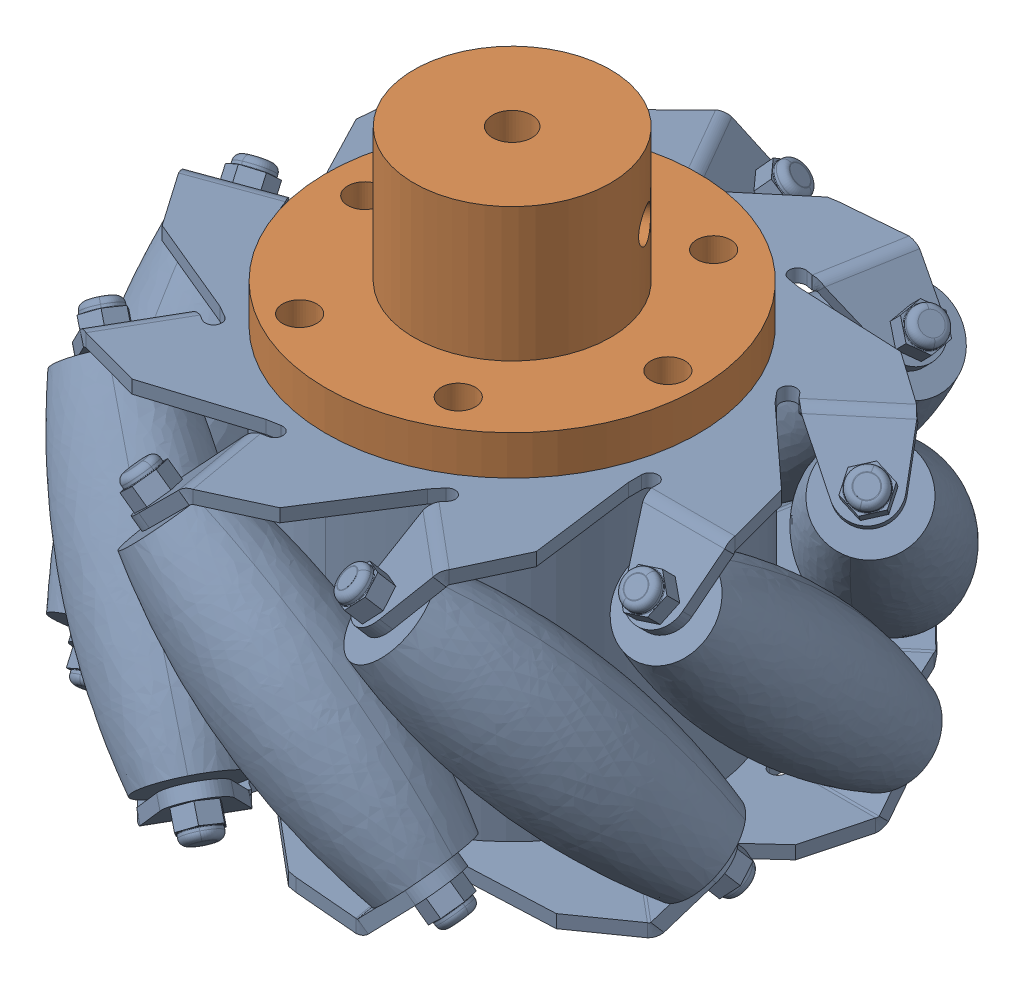
SolidWorks assembly 100mm_LF, configuration 默认. Lengths in mm.
Overall size (102.05 76.39 102.38).
2 component instances, 2 part files, 4 mates.
Components (placement in the parent):
- 100mm_LF-1: 100mm_LF [默认] at origin size (102.05 50.01 102.38)
- 6mm_TightCoupling-2: 6mm_TightCoupling [默认] at (0 47.9113 0) x (-0.5 0 -0.866025) z (0 1 0) size (56.8 56.8 26.4)
Mates (geometry in assembly coordinates):
- 同心3: concentric: cylinder of 100mm_LF-1 through (-11.875 47.9113 -20.5681) axis (0 -1 0) radius 2.5; cylinder of 6mm_TightCoupling-2 through (-11.875 47.9113 -20.5681) axis (0 1 0) radius 2.6
- 同心4: concentric: cylinder of 100mm_LF-1 through (23.75 47.9113 0) axis (0 -1 0) radius 2.5; cylinder of 6mm_TightCoupling-2 through (23.75 47.9113 0) axis (0 1 0) radius 2.6
- 同心5: concentric: cylinder of 100mm_LF-1 through (-11.875 47.9113 20.5681) axis (0 -1 0) radius 2.5; cylinder of 6mm_TightCoupling-2 through (-11.875 47.9113 20.5681) axis (0 1 0) radius 2.6
- 重合1: coincident anti-aligned: plane of 100mm_LF-1 through (0 47.9113 0) normal (0 1 0); plane of 6mm_TightCoupling-2 through (3.8049 47.9113 6.5902) normal (0 -1 0)
